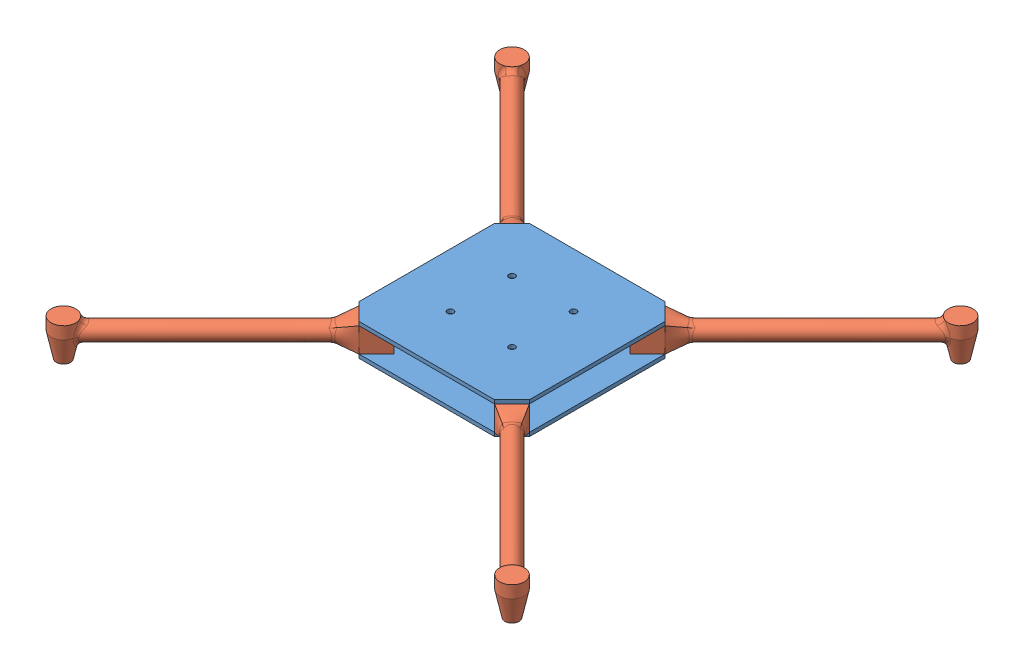
SolidWorks assembly Assem2, configuration Default. Lengths in mm.
Overall size (392.84 33 392.84).
6 component instances, 2 part files, 14 mates.
Components (placement in the parent):
- base_plate-1: base_plate [Default] at (57.0322 62.9833 108.5062) size (138.28 3 138.28)
- arm_1-1: arm_1 [Default] at (119.1033 75.9833 170.5773) x (0 1 0) z (0.707107 0 -0.707107) size (30 200 20)
- arm_1-2: arm_1 [Default] at (-5.0388 75.9833 170.5773) x (0 1 0) z (0.707107 0 0.707107) size (30 200 20)
- arm_1-4: arm_1 [Default] at (119.1033 75.9833 46.4352) x (0 1 0) z (-0.707107 0 -0.707107) size (30 200 20)
- arm_1-5: arm_1 [Default] at (-5.0388 75.9833 46.4352) x (0 1 0) z (-0.707107 0 0.707107) size (30 200 20)
- base_plate-2: base_plate [Default] at (57.0322 85.9833 108.5062) size (138.28 3 138.28)
Mates (geometry in assembly coordinates):
- Coincident2: coincident: point of base_plate-1; point of arm_1-1
- Coincident3: coincident: unknown of base_plate-1
- Coincident5: coincident: point of base_plate-1; point of arm_1-2
- Coincident6: coincident: point of base_plate-1; point of arm_1-2
- Coincident8: coincident: point of arm_1-5; point of base_plate-1
- Coincident9: coincident: point of base_plate-1; point of arm_1-5
- Coincident10: coincident: point of base_plate-1; point of arm_1-4
- Coincident12: coincident: unknown of base_plate-1
- Coincident13: coincident anti-aligned: plane of base_plate-1 through (57.0322 65.9833 108.5062) normal (0 1 0); plane of arm_1-5 through (16.1744 65.9833 53.5062) normal (0 -1 0)
- Coincident14: coincident anti-aligned: plane of base_plate-1 through (57.0322 65.9833 108.5062) normal (0 1 0); plane of arm_1-2 through (2.0322 65.9833 149.3641) normal (0 -1 0)
- Coincident16: coincident anti-aligned: plane of base_plate-1 through (57.0322 65.9833 108.5062) normal (0 1 0); plane of arm_1-1 through (97.8901 65.9833 163.5062) normal (0 -1 0)
- Coincident17: coincident anti-aligned: plane of base_plate-1 through (57.0322 65.9833 108.5062) normal (0 1 0); plane of arm_1-4 through (112.0322 65.9833 67.6484) normal (0 -1 0)
- Coincident19: coincident anti-aligned: line of arm_1-4 through (126.1744 85.9833 53.5062) axis (-0.707107 0 -0.707107); line of base_plate-2 through (112.0322 85.9833 39.3641) axis (0.707107 0 0.707107)
- Coincident20: coincident aligned: line of arm_1-1 through (112.0322 85.9833 177.6484) axis (0.707107 0 -0.707107); line of base_plate-2 through (112.0322 85.9833 177.6484) axis (0.707107 0 -0.707107)
